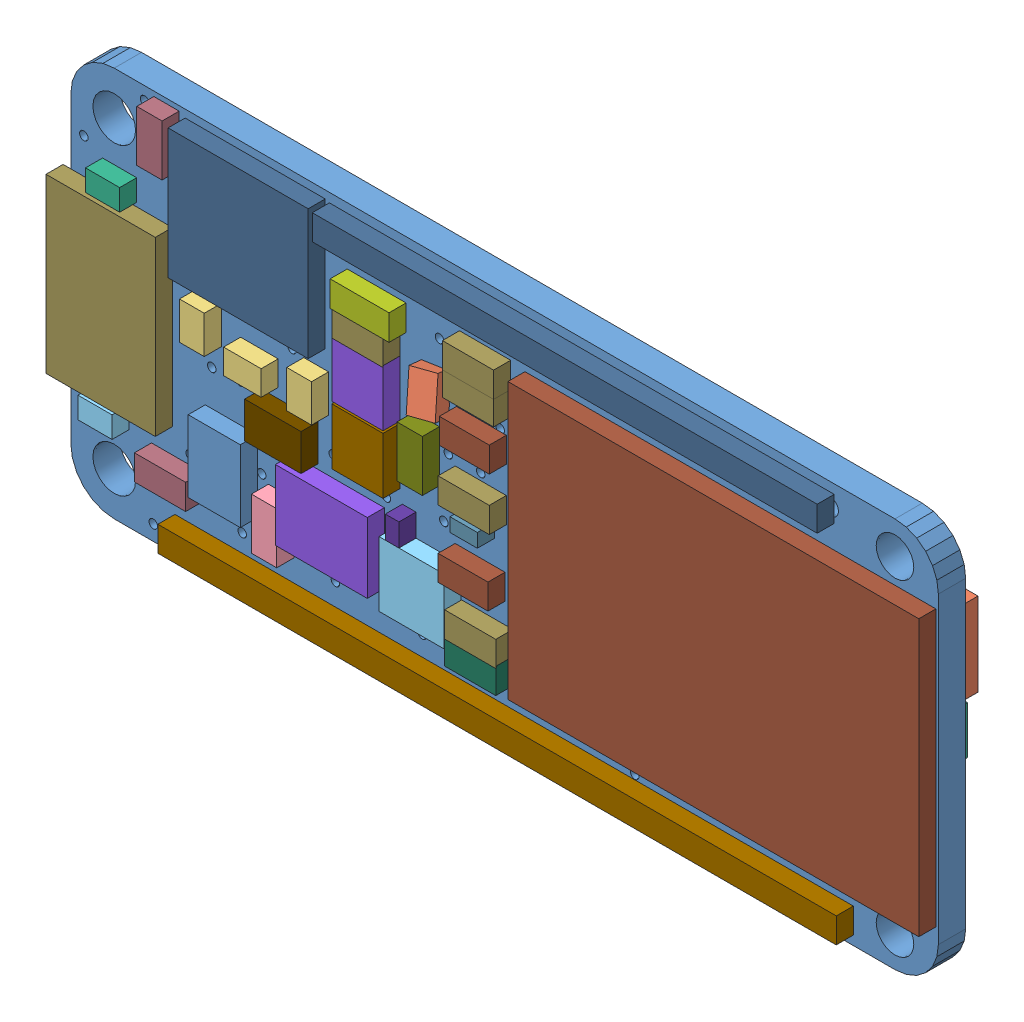
SolidWorks assembly adafruit esp8266 feather, configuration Default. Lengths in mm.
Overall size (51.25 22.86 3.97).
39 component instances, 30 part files, 0 mates.
Components (placement in the parent):
- adafruit esp8266 feather-1: adafruit esp8266 feather [Default] at origin size (50.8 22.86 1.6)
- 0805NO_10UF-1: 0805NO_10UF [Default] at (21.3793 16.0687 1.6213) x (0.148132 -0.963382 0.223501) z (0.165546 0.24696 0.95478) size (2.2 1.45 1)
- 0805NO_10_F-1: 0805NO_10_F [Default] at (11.049 12.192 1.6) x (-1 0 0) z (0 0 1) size (2.2 1.45 1)
- 0805NO_10_F-2: 0805NO_10_F [Default] at (8.088 12.959 1.6) x (0 1 0) z (0 0 1) size (2.2 1.45 1)
- 0805NO_10_F-3: 0805NO_10_F [Default] at (14.366 12.64 1.6) x (0 -1 0) z (0 0 1) size (2.2 1.45 1)
- 0603NO_1UF-1: 0603NO_1UF [Default] at (12.302 4.775 1.6) x (0 -1 0) z (0 0 1) size (3 1.48 1)
- CHIPLED_0805_NOOUTLINE_ORANGE-1: CHIPLED_0805_NOOUTLINE_ORANGE [Default] at (2.413 5.588 1.6) x (0 -1 0) z (0 0 1) size (1.25 2 1)
- CHIPLED_0805_NOOUTLINE_RED-1: CHIPLED_0805_NOOUTLINE_RED [Default] at (2.8575 17.3355 1.6) x (0 -1 0) z (0 0 1) size (1.25 2 1)
- SOD123_MBR120-1: SOD123_MBR120 [Default] at (17.907 18.796 1.6) x (-1 0 0) z (0 0 1) size (3.45 1.5 1)
- QFN24_4MM_SMSC_CP2104-1: QFN24_4MM_SMSC_CP2104 [Default] at (16.256 6.477 1.6) size (5.38 4.1 1)
- 1X16_ROUND_JP1_1X16_ROUND-1: 1X16_ROUND_JP1_1X16_ROUND [Default] at (25.4 1.27 1.6) x (-1 0 0) z (0 0 1) size (39.73 1.47 1)
- 1X12_ROUND_JP3_1X12_ROUND-1: 1X12_ROUND_JP3_1X12_ROUND [Default] at (30.48 21.59 1.6) size (29.57 1.47 1)
- SOT233_MMBT2222-1: SOT233_MMBT2222 [Default] at (24.003 8.001 1.6) x (-1 0 0) z (0 0 1) size (2.92 1.47 1)
- SOT233_MMBT2222-2: SOT233_MMBT2222 [Default] at (24.003 14.986 1.6) size (2.92 1.47 1)
- 0603NO_10K-1: 0603NO_10K [Default] at (24.257 18.923 1.6) x (-1 0 0) z (0 0 1) size (3 1.48 1)
- 0603NO_10K-2: 0603NO_10K [Default] at (24.257 17.526 1.6) x (-1 0 0) z (0 0 1) size (3 1.48 1)
- 0603NO_10K-3: 0603NO_10K [Default] at (24.003 11.938 1.6) x (-1 0 0) z (0 0 1) size (3 1.48 1)
- 0603NO_10K-4: 0603NO_10K [Default] at (17.78 17.272 1.6) size (3 1.48 1)
- 0603NO_10K-5: 0603NO_10K [Default] at (24.384 5.334 1.6) x (-1 0 0) z (0 0 1) size (3 1.48 1)
- 0603NO_1K-1: 0603NO_1K [Default] at (6.223 4.191 1.6) size (3 1.48 1)
- 0603NO_1K-2: 0603NO_1K [Default] at (5.588 21.082 1.6) x (0 -1 0) z (0 0 1) size (3 1.48 1)
- _0603MP_10K-1: _0603MP_10K [Default] at (24.003 10.541 1.6) size (1.6 0.8 1)
- 0603NO_4_7K-1: 0603NO_4_7K [Default] at (24.384 3.937 1.6) size (3 1.48 1)
- 0603NO_10K_-1: 0603NO_10K_ [Default] at (20.828 12.7 1.6) x (0 -1 0) z (0 0 1) size (3 1.48 1)
- _0603MP_1K-1: _0603MP_1K [Default] at (19.812 8.382 1.6) x (0 -1 0) z (0 0 1) size (1.6 0.8 1)
- SOLDERJUMPER_CLOSEDWIRE_SJ1_SOLDERJUMPER_CLOSEDWIRE-1: SOLDERJUMPER_CLOSEDWIRE_SJ1_SOLDERJUMPER_CLOSEDWIRE [Default] at (12.827 9.779 1.6) x (-1 0 0) z (0 0 1) size (3.3 2.13 1)
- BTN_KMR2_4_6X2_8_KMR2-1: BTN_KMR2_4_6X2_8_KMR2 [Default] at (9.398 6.35 1.6) x (0 -1 0) z (0 0 1) size (4.2 3.05 1)
- ADAFRUIT_5MM_U_7_ADAFRUIT_5MM-1: ADAFRUIT_5MM_U_7_ADAFRUIT_5MM [Default] at (45.6565 13.9065 0) x (0 1 0) z (0 0 -1) size (4.88 4.87 1)
- FEATHERLOGO_U_9_FEATHERLOGO-1: FEATHERLOGO_U_9_FEATHERLOGO [Default] at (30.6705 4.8895 0) x (-1 0 0) z (0 0 -1) size (24.3 11.26 1)
- PCBFEATREV040_U_13_PCBFEATREV040-1: PCBFEATREV040_U_13_PCBFEATREV040 [Default] at (4.6355 11.2395 0) x (-1 0 0) z (0 0 -1) size (2.1 2.1 1)
- ADAFRUIT_3_5MM_U_15_ADAFRUIT_3_5MM-1: ADAFRUIT_3_5MM_U_15_ADAFRUIT_3_5MM [Default] at (19.05 4.064 1.6) size (3.79 3.79 1)
- HUZZAHLOGO_U_23_HUZZAHLOGO-1: HUZZAHLOGO_U_23_HUZZAHLOGO [Default] at (49.911 10.287 0) x (-1 0 0) z (0 0 -1) size (17.77 2.78 1)
- FIDUCIAL_1MM_FIDUCIAL__-1: FIDUCIAL_1MM_FIDUCIAL__ [Default] at (10.795 20.066 1.6) x (0 -1 0) z (0 0 1) size (1.25 1.25 1)
- FIDUCIAL_1MM_FIDUCIAL__-2: FIDUCIAL_1MM_FIDUCIAL__ [Default] at (41.5762 11.691 1.6) x (0 -1 0) z (0 0 1) size (1.25 1.25 1)
- SOT235_SPX3819-1: SOT235_SPX3819 [Default] at (17.78 14.986 1.6) x (0 1 0) z (0 0 1) size (3.3 3 1)
- SOT235_MCP73831T2ACI_OT-1: SOT235_MCP73831T2ACI_OT [Default] at (17.78 11.557 1.6) x (0 -1 0) z (0 0 1) size (3.3 3 1)
- JSTPH2_JSTPH-1: JSTPH2_JSTPH [Default] at (10.795 19.304 1.6) size (8.2 7.6 1)
- ESP12E_ESP12-1: ESP12E_ESP12 [Default] at (36.322 11.43 1.6) x (0 -1 0) z (0 0 1) size (16.13 24.06 1)
- 4UCONN_20329_V2_20329-1: 4UCONN_20329_V2_20329 [Default] at (4.445 11.43 1.6) x (0 -1 0) z (0 0 1) size (10.1 6.4 1)
